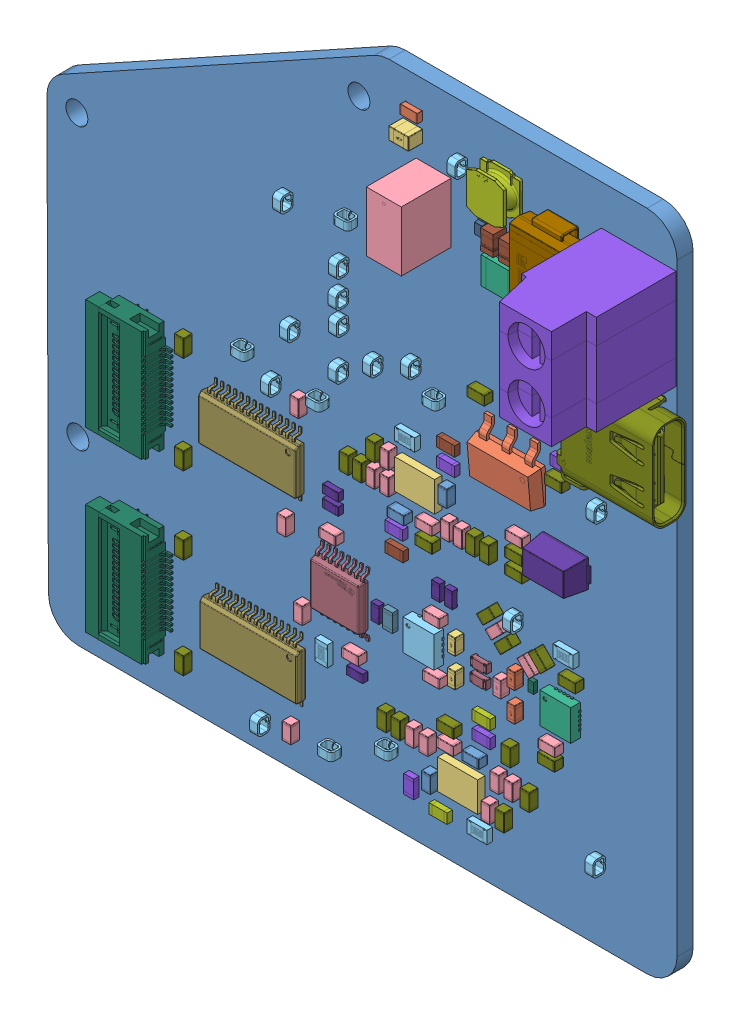
SolidWorks assembly StewartPlatform, configuration Default. Lengths in mm.
Overall size (64.08 66.48 15.5).
190 component instances, 42 part files, 0 mates.
Components (placement in the parent):
- StewartPlatform_BOARD-1: StewartPlatform_BOARD [Default] at origin size (63.17 66.48 1.61)
- RESC1608X55X25NL10T15_CMP-009-00195-1-1: RESC1608X55X25NL10T15_CMP-009-00195-1 [Default] at (81.6864 120.2944 1.5964) x (-1 0 0) z (0 0 1) size (1.7 0.9 0.55)
- FP-CL21-IPC_C_CMP-001-00099-1-1: FP-CL21-IPC_C_CMP-001-00099-1 [Default] at (81.5594 118.5418 1.5964) x (-1 0 0) z (0 0 1) size (2.08 1.33 1.53)
- CAPC1608X90X40NL10T20_CMP-001-00092-1-1: CAPC1608X90X40NL10T20_CMP-001-00092-1 [Default] at (84.2518 77.8764 1.5964) x (-1 0 0) z (0 0 1) size (1.7 0.9 0.9)
- CAPC1608X90X40NL10T20_CMP-001-00092-1-2: CAPC1608X90X40NL10T20_CMP-001-00092-1 [Default] at (84.2518 72.644 1.5964) x (-1 0 0) z (0 0 1) size (1.7 0.9 0.9)
- CAPC1608X90X40NL10T20_CMP-001-00092-1-3: CAPC1608X90X40NL10T20_CMP-001-00092-1 [Default] at (73.8378 79.8322 1.5964) size (1.7 0.9 0.9)
- CAPC1608X90X40NL10T20_CMP-001-00092-1-4: CAPC1608X90X40NL10T20_CMP-001-00092-1 [Default] at (69.2658 78.5622 1.5964) x (0 1 0) z (0 0 1) size (1.7 0.9 0.9)
- CAPC1608X90X40NL10T20_CMP-001-00092-1-5: CAPC1608X90X40NL10T20_CMP-001-00092-1 [Default] at (69.7738 60.7822 1.5964) x (0 1 0) z (0 0 1) size (1.7 0.9 0.9)
- CAPC1608X90X40NL10T20_CMP-001-00092-1-6: CAPC1608X90X40NL10T20_CMP-001-00092-1 [Default] at (76.1238 70.5612 1.5964) x (-1 0 0) z (0 0 1) size (1.7 0.9 0.9)
- CAPC1608X90X40NL10T20_CMP-001-00092-1-7: CAPC1608X90X40NL10T20_CMP-001-00092-1 [Default] at (70.5358 89.4842 1.5964) x (0 -1 0) z (0 0 1) size (1.7 0.9 0.9)
- CAPC1608X90X40NL10T20_CMP-001-00092-1-8: CAPC1608X90X40NL10T20_CMP-001-00092-1 [Default] at (70.9168 71.7042 1.5964) x (0 -1 0) z (0 0 1) size (1.7 0.9 0.9)
- CAPC1608X90X40NL10T20_CMP-001-00092-1-9: CAPC1608X90X40NL10T20_CMP-001-00092-1 [Default] at (65.913 102.1334 0.0102) x (0 -1 0) z (0 0 -1) size (1.7 0.9 0.9)
- CAPC1608X90X40NL10T20_CMP-001-00092-1-10: CAPC1608X90X40NL10T20_CMP-001-00092-1 [Default] at (62.9666 75.8444 0.0102) x (1 0 0) z (0 0 -1) size (1.7 0.9 0.9)
- CAPC1608X90X40NL10T20_CMP-001-00092-1-11: CAPC1608X90X40NL10T20_CMP-001-00092-1 [Default] at (82.0928 66.6242 1.5964) x (0 -1 0) z (0 0 1) size (1.7 0.9 0.9)
- CAPC1608X90X40NL10T20_CMP-001-00092-1-12: CAPC1608X90X40NL10T20_CMP-001-00092-1 [Default] at (83.4898 66.6242 1.5964) x (0 -1 0) z (0 0 1) size (1.7 0.9 0.9)
- CAPC1608X90X40NL10T20_CMP-001-00092-1-13: CAPC1608X90X40NL10T20_CMP-001-00092-1 [Default] at (85.6488 67.5132 1.5964) size (1.7 0.9 0.9)
- CAPC1608X90X40NL10T20_CMP-001-00092-1-14: CAPC1608X90X40NL10T20_CMP-001-00092-1 [Default] at (90.6018 66.8782 1.5964) x (0 1 0) z (0 0 1) size (1.7 0.9 0.9)
- CAPC1608X90X40NL10T20_CMP-001-00092-1-15: CAPC1608X90X40NL10T20_CMP-001-00092-1 [Default] at (91.9988 66.8782 1.5964) x (0 1 0) z (0 0 1) size (1.7 0.9 0.9)
- CAPC1608X90X40NL10T20_CMP-001-00092-1-16: CAPC1608X90X40NL10T20_CMP-001-00092-1 [Default] at (89.7128 63.8302 1.5964) x (0 -1 0) z (0 0 1) size (1.7 0.9 0.9)
- CAPC1608X90X40NL10T20_CMP-001-00092-1-17: CAPC1608X90X40NL10T20_CMP-001-00092-1 [Default] at (86.9188 86.3092 1.5964) x (0 1 0) z (0 0 1) size (1.7 0.9 0.9)
- CAPC1608X90X40NL10T20_CMP-001-00092-1-18: CAPC1608X90X40NL10T20_CMP-001-00092-1 [Default] at (85.6488 86.3092 1.5964) x (0 1 0) z (0 0 1) size (1.7 0.9 0.9)
- CAPC1608X90X40NL10T20_CMP-001-00092-1-19: CAPC1608X90X40NL10T20_CMP-001-00092-1 [Default] at (83.4898 85.5472 1.5964) x (-1 0 0) z (0 0 1) size (1.7 0.9 0.9)
- CAPC1608X90X40NL10T20_CMP-001-00092-1-20: CAPC1608X90X40NL10T20_CMP-001-00092-1 [Default] at (61.5188 60.9092 0.0102) x (1 0 0) z (0 0 -1) size (1.7 0.9 0.9)
- CAPC1608X90X40NL10T20_CMP-001-00092-1-21: CAPC1608X90X40NL10T20_CMP-001-00092-1 [Default] at (78.1558 87.1474 1.5964) x (0 -1 0) z (0 0 1) size (1.7 0.9 0.9)
- CAPC1608X90X40NL10T20_CMP-001-00092-1-22: CAPC1608X90X40NL10T20_CMP-001-00092-1 [Default] at (79.5528 87.1728 1.5964) x (0 -1 0) z (0 0 1) size (1.7 0.9 0.9)
- CAPC1608X90X40NL10T20_CMP-001-00092-1-23: CAPC1608X90X40NL10T20_CMP-001-00092-1 [Default] at (79.5528 89.4842 1.5964) x (0 1 0) z (0 0 1) size (1.7 0.9 0.9)
- CAPC1608X90X40NL10T20_CMP-001-00092-1-24: CAPC1608X90X40NL10T20_CMP-001-00092-1 [Default] at (92.5322 88.9762 1.5964) size (1.7 0.9 0.9)
- CAPC1608X90X40NL10T20_CMP-001-00092-1-25: CAPC1608X90X40NL10T20_CMP-001-00092-1 [Default] at (93.7768 78.5114 1.5964) x (0.707107 -0.707107 0) z (0 0 1) size (1.7 0.9 0.9)
- CAPC1608X90X40NL10T20_CMP-001-00092-1-26: CAPC1608X90X40NL10T20_CMP-001-00092-1 [Default] at (90.5764 79.9846 1.5964) x (0.707107 0.707107 0) z (0 0 1) size (1.7 0.9 0.9)
- CAPC1608X90X40NL10T20_CMP-001-00092-1-27: CAPC1608X90X40NL10T20_CMP-001-00092-1 [Default] at (95.8342 72.4916 1.5964) x (-1 0 0) z (0 0 1) size (1.7 0.9 0.9)
- FP-S2761-46R-MFG_CMP-002-00072-3-1: FP-S2761-46R-MFG_CMP-002-00072-3 [Default] at (74.7522 103.6828 1.5964) x (0 1 0) z (0 0 1) size (1.6 0.8 1.28)
- FP-S2761-46R-MFG_CMP-002-00072-3-2: FP-S2761-46R-MFG_CMP-002-00072-3 [Default] at (75.4888 108.077 1.5964) x (-1 0 0) z (0 0 1) size (1.6 0.8 1.28)
- FP-S2761-46R-MFG_CMP-002-00072-3-3: FP-S2761-46R-MFG_CMP-002-00072-3 [Default] at (74.7268 94.5642 1.5964) x (0 1 0) z (0 0 1) size (1.6 0.8 1.28)
- FP-S2761-46R-MFG_CMP-002-00072-3-4: FP-S2761-46R-MFG_CMP-002-00072-3 [Default] at (74.7522 98.6282 1.5964) x (0 -1 0) z (0 0 1) size (1.6 0.8 1.28)
- FP-S2761-46R-MFG_CMP-002-00072-3-5: FP-S2761-46R-MFG_CMP-002-00072-3 [Default] at (81.9912 98.5774 1.5964) x (0 -1 0) z (0 0 1) size (1.6 0.8 1.28)
- FP-S2761-46R-MFG_CMP-002-00072-3-6: FP-S2761-46R-MFG_CMP-002-00072-3 [Default] at (78.1812 96.8248 1.5964) x (0 1 0) z (0 0 1) size (1.6 0.8 1.28)
- FP-S2761-46R-MFG_CMP-002-00072-3-7: FP-S2761-46R-MFG_CMP-002-00072-3 [Default] at (84.3026 96.8756 1.5964) x (-1 0 0) z (0 0 1) size (1.6 0.8 1.28)
- FP-S2761-46R-MFG_CMP-002-00072-3-8: FP-S2761-46R-MFG_CMP-002-00072-3 [Default] at (74.7268 100.965 1.5964) x (0 -1 0) z (0 0 1) size (1.6 0.8 1.28)
- FP-S2761-46R-MFG_CMP-002-00072-3-9: FP-S2761-46R-MFG_CMP-002-00072-3 [Default] at (69.85 95.7326 1.5964) x (0 1 0) z (0 0 1) size (1.6 0.8 1.28)
- FP-S2761-46R-MFG_CMP-002-00072-3-10: FP-S2761-46R-MFG_CMP-002-00072-3 [Default] at (72.6186 90.932 1.5964) x (-1 0 0) z (0 0 1) size (1.6 0.8 1.28)
- FP-S2761-46R-MFG_CMP-002-00072-3-11: FP-S2761-46R-MFG_CMP-002-00072-3 [Default] at (78.2574 99.187 0.0102) x (0 -1 0) z (0 0 -1) size (1.6 0.8 1.28)
- FP-S2761-46R-MFG_CMP-002-00072-3-12: FP-S2761-46R-MFG_CMP-002-00072-3 [Default] at (69.1642 106.553 1.5964) x (0 -1 0) z (0 0 1) size (1.6 0.8 1.28)
- FP-S2761-46R-MFG_CMP-002-00072-3-13: FP-S2761-46R-MFG_CMP-002-00072-3 [Default] at (79.5274 64.1096 1.5964) x (-1 0 0) z (0 0 1) size (1.6 0.8 1.28)
- FP-S2761-46R-MFG_CMP-002-00072-3-14: FP-S2761-46R-MFG_CMP-002-00072-3 [Default] at (66.8782 60.0456 1.5964) x (0 1 0) z (0 0 1) size (1.6 0.8 1.28)
- FP-S2761-46R-MFG_CMP-002-00072-3-15: FP-S2761-46R-MFG_CMP-002-00072-3 [Default] at (86.6648 118.3132 1.5964) x (0 -1 0) z (0 0 1) size (1.6 0.8 1.28)
- FP-S2761-46R-MFG_CMP-002-00072-3-16: FP-S2761-46R-MFG_CMP-002-00072-3 [Default] at (100.6094 95.3516 1.5964) x (0 -1 0) z (0 0 1) size (1.6 0.8 1.28)
- FP-S2761-46R-MFG_CMP-002-00072-3-17: FP-S2761-46R-MFG_CMP-002-00072-3 [Default] at (73.8378 61.1886 1.5964) x (-1 0 0) z (0 0 1) size (1.6 0.8 1.28)
- FP-S2761-46R-MFG_CMP-002-00072-3-18: FP-S2761-46R-MFG_CMP-002-00072-3 [Default] at (65.1002 91.567 1.5964) x (-1 0 0) z (0 0 1) size (1.6 0.8 1.28)
- FP-S2761-46R-MFG_CMP-002-00072-3-19: FP-S2761-46R-MFG_CMP-002-00072-3 [Default] at (92.2274 81.6102 1.5964) x (0 -1 0) z (0 0 1) size (1.6 0.8 1.28)
- FP-S2761-46R-MFG_CMP-002-00072-3-20: FP-S2761-46R-MFG_CMP-002-00072-3 [Default] at (67.9704 90.043 1.5964) x (0 1 0) z (0 0 1) size (1.6 0.8 1.28)
- FP-S2761-46R-MFG_CMP-002-00072-3-21: FP-S2761-46R-MFG_CMP-002-00072-3 [Default] at (100.4824 64.5668 1.5964) x (0 1 0) z (0 0 1) size (1.6 0.8 1.28)
- RESC3126X60X50NL10T20_CMP-009-00179-1-1: RESC3126X60X50NL10T20_CMP-009-00179-1 [Default] at (90.5764 110.4138 1.5964) x (-1 0 0) z (0 0 1) size (3.2 2.7 0.6)
- FP-LQH44PH_PR-MFG_CMP-06042-017138-1-1: FP-LQH44PH_PR-MFG_CMP-06042-017138-1 [Default] at (90.5764 118.0338 1.5964) x (-1 0 0) z (0 0 1) size (4.01 4 1.95)
- 691137710002_CMP-002-00078-1-1: 691137710002_CMP-002-00078-1 [Default] at (104.2924 114.6048 1.5964) x (0 -1 0) z (0 0 1) size (10 7.5 15.1)
- FP-DO-214AB_SMC_J-Bend-MFG_CMP-004-00033-1-1: FP-DO-214AB_SMC_J-Bend-MFG_CMP-004-00033-1 [Default] at (96.6724 114.6048 1.5964) x (0 -1 0) z (0 0 1) size (7.97 5.92 2.66)
- WL-SMCW_0603_150060xx75000_CMP-007-00036-1-1: WL-SMCW_0603_150060xx75000_CMP-007-00036-1 [Default] at (88.7984 113.8428 1.5964) x (0 1 0) z (0 0 1) size (1.6 0.8 0.7)
- CL21A226MOQNNNE-Footprint-1_CMP-001-00087-3-1: CL21A226MOQNNNE-Footprint-1_CMP-001-00087-3 [Default] at (90.3224 113.8428 1.5964) x (0 1 0) z (0 0 1) size (2 1.25 1.35)
- CL21A226MOQNNNE-Footprint-1_CMP-001-00087-3-2: CL21A226MOQNNNE-Footprint-1_CMP-001-00087-3 [Default] at (92.1004 113.8428 1.5964) x (0 1 0) z (0 0 1) size (2 1.25 1.35)
- TSOP65P640X120-28M_CMP-00000-1-1: TSOP65P640X120-28M_CMP-00000-1 [Default] at (66.2178 66.2432 1.5964) x (0 -1 0) z (0 0 1) size (6.4 9.8 1.2)
- TSOP65P640X120-28M_CMP-00000-1-2: TSOP65P640X120-28M_CMP-00000-1 [Default] at (66.0908 84.0232 1.5964) x (0 -1 0) z (0 0 1) size (6.4 9.8 1.2)
- FP-PW0016A-IPC_B_CMP-002-00081-1-1: FP-PW0016A-IPC_B_CMP-002-00081-1 [Default] at (74.8538 75.2602 1.5964) x (0 -1 0) z (0 0 1) size (6.4 5.01 1.21)
- FP-318-08-IPC_B_CMP-07173-000101-1-1: FP-318-08-IPC_B_CMP-07173-000101-1 [Default] at (53.312 65.1247 0.0102) x (0 1 0) z (0 0 -1) size (2.4 2.92 1.14)
- FP-318-08-IPC_B_CMP-07173-000101-1-2: FP-318-08-IPC_B_CMP-07173-000101-1 [Default] at (56.6166 64.7192 0.0102) x (0 1 0) z (0 0 -1) size (2.4 2.92 1.14)
- FP-318-08-IPC_B_CMP-07173-000101-1-3: FP-318-08-IPC_B_CMP-07173-000101-1 [Default] at (94.9732 99.3403 0.0102) x (0 -1 0) z (0 0 -1) size (2.4 2.92 1.14)
- FP-318-08-IPC_B_CMP-07173-000101-1-4: FP-318-08-IPC_B_CMP-07173-000101-1 [Default] at (75.9688 82.9555 0.0102) x (0 1 0) z (0 0 -1) size (2.4 2.92 1.14)
- FP-318-08-IPC_B_CMP-07173-000101-1-5: FP-318-08-IPC_B_CMP-07173-000101-1 [Default] at (60.3504 85.2424 0.0102) x (0 1 0) z (0 0 -1) size (2.4 2.92 1.14)
- FP-318-08-IPC_B_CMP-07173-000101-1-6: FP-318-08-IPC_B_CMP-07173-000101-1 [Default] at (71.2428 87.188 0.0102) x (-1 0 0) z (0 0 -1) size (2.4 2.92 1.14)
- FP-318-08-IPC_B_CMP-07173-000101-1-7: FP-318-08-IPC_B_CMP-07173-000101-1 [Default] at (71.2724 83.058 0.0102) x (-1 0 0) z (0 0 -1) size (2.4 2.92 1.14)
- FP-318-08-IPC_B_CMP-07173-000101-1-8: FP-318-08-IPC_B_CMP-07173-000101-1 [Default] at (101.1936 71.8016 0.0102) x (0 1 0) z (0 0 -1) size (2.4 2.92 1.14)
- FP-318-08-IPC_B_CMP-07173-000101-1-9: FP-318-08-IPC_B_CMP-07173-000101-1 [Default] at (92.7058 61.6864 0.0102) x (-1 0 0) z (0 0 -1) size (2.4 2.92 1.14)
- FP-318-08-IPC_B_CMP-07173-000101-1-10: FP-318-08-IPC_B_CMP-07173-000101-1 [Default] at (100.5078 62.4586 0.0102) x (0 1 0) z (0 0 -1) size (2.4 2.92 1.14)
- FP-318-08-IPC_B_CMP-07173-000101-1-11: FP-318-08-IPC_B_CMP-07173-000101-1 [Default] at (102.1842 81.2546 0.0102) x (0 -1 0) z (0 0 -1) size (2.4 2.92 1.14)
- FP-318-08-IPC_B_CMP-07173-000101-1-12: FP-318-08-IPC_B_CMP-07173-000101-1 [Default] at (78.2828 63.0428 0.0102) x (0 -1 0) z (0 0 -1) size (2.4 2.92 1.14)
- 687114149022_CMP-002-00080-1-1: 687114149022_CMP-002-00080-1 [Default] at (53.8988 66.3702 1.5964) x (0 -1 0) z (0 0 1) size (11.1 6.5 2.25)
- 687114149022_CMP-002-00080-1-2: 687114149022_CMP-002-00080-1 [Default] at (53.8988 84.1502 1.5964) x (0 -1 0) z (0 0 1) size (11.1 6.5 2.25)
- CAPC1608X90X35NL15T15_CMP-001-00004-8-1: CAPC1608X90X35NL15T15_CMP-001-00004-8 [Default] at (58.9788 61.4172 1.5964) x (0 1 0) z (0 0 1) size (1.75 0.95 0.9)
- CAPC1608X90X35NL15T15_CMP-001-00004-8-2: CAPC1608X90X35NL15T15_CMP-001-00004-8 [Default] at (58.9788 88.9762 1.5964) x (0 -1 0) z (0 0 1) size (1.75 0.95 0.9)
- CAPC1608X90X35NL15T15_CMP-001-00004-8-3: CAPC1608X90X35NL15T15_CMP-001-00004-8 [Default] at (58.9788 79.1972 1.5964) x (0 1 0) z (0 0 1) size (1.75 0.95 0.9)
- CAPC1608X90X35NL15T15_CMP-001-00004-8-4: CAPC1608X90X35NL15T15_CMP-001-00004-8 [Default] at (58.9788 71.4502 1.5964) x (0 -1 0) z (0 0 1) size (1.75 0.95 0.9)
- CAPC1608X90X35NL15T15_CMP-001-00004-8-5: CAPC1608X90X35NL15T15_CMP-001-00004-8 [Default] at (73.914 107.3658 0.0102) x (-1 0 0) z (0 0 -1) size (1.75 0.95 0.9)
- CAPC1608X90X35NL15T15_CMP-001-00004-8-6: CAPC1608X90X35NL15T15_CMP-001-00004-8 [Default] at (68.2244 71.4502 0.0102) x (1 0 0) z (0 0 -1) size (1.75 0.95 0.9)
- CAPC1608X90X35NL15T15_CMP-001-00004-8-7: CAPC1608X90X35NL15T15_CMP-001-00004-8 [Default] at (62.992 73.3298 0.0102) x (1 0 0) z (0 0 -1) size (1.75 0.95 0.9)
- CAPC1608X90X35NL15T15_CMP-001-00004-8-8: CAPC1608X90X35NL15T15_CMP-001-00004-8 [Default] at (62.992 74.6252 0.0102) x (1 0 0) z (0 0 -1) size (1.75 0.95 0.9)
- CAPC1608X90X35NL15T15_CMP-001-00004-8-9: CAPC1608X90X35NL15T15_CMP-001-00004-8 [Default] at (60.96 75.2856 0.0102) x (0 1 0) z (0 0 -1) size (1.75 0.95 0.9)
- CAPC1608X90X35NL15T15_CMP-001-00004-8-10: CAPC1608X90X35NL15T15_CMP-001-00004-8 [Default] at (79.2988 66.6242 1.5964) x (0 -1 0) z (0 0 1) size (1.75 0.95 0.9)
- CAPC1608X90X35NL15T15_CMP-001-00004-8-11: CAPC1608X90X35NL15T15_CMP-001-00004-8 [Default] at (80.6958 66.6242 1.5964) x (0 -1 0) z (0 0 1) size (1.75 0.95 0.9)
- CAPC1608X90X35NL15T15_CMP-001-00004-8-12: CAPC1608X90X35NL15T15_CMP-001-00004-8 [Default] at (85.6488 69.0372 1.5964) size (1.75 0.95 0.9)
- CAPC1608X90X35NL15T15_CMP-001-00004-8-13: CAPC1608X90X35NL15T15_CMP-001-00004-8 [Default] at (91.7448 69.7992 1.5964) x (0 -1 0) z (0 0 1) size (1.75 0.95 0.9)
- CAPC1608X90X35NL15T15_CMP-001-00004-8-14: CAPC1608X90X35NL15T15_CMP-001-00004-8 [Default] at (93.6498 66.8782 1.5964) x (0 1 0) z (0 0 1) size (1.75 0.95 0.9)
- CAPC1608X90X35NL15T15_CMP-001-00004-8-15: CAPC1608X90X35NL15T15_CMP-001-00004-8 [Default] at (91.1098 63.8302 1.5964) x (0 -1 0) z (0 0 1) size (1.75 0.95 0.9)
- CAPC1608X90X35NL15T15_CMP-001-00004-8-16: CAPC1608X90X35NL15T15_CMP-001-00004-8 [Default] at (69.596 58.039 0.0102) x (-1 0 0) z (0 0 -1) size (1.75 0.95 0.9)
- CAPC1608X90X35NL15T15_CMP-001-00004-8-17: CAPC1608X90X35NL15T15_CMP-001-00004-8 [Default] at (89.5858 86.3092 1.5964) x (0 1 0) z (0 0 1) size (1.75 0.95 0.9)
- CAPC1608X90X35NL15T15_CMP-001-00004-8-18: CAPC1608X90X35NL15T15_CMP-001-00004-8 [Default] at (88.1888 86.3092 1.5964) x (0 1 0) z (0 0 1) size (1.75 0.95 0.9)
- CAPC1608X90X35NL15T15_CMP-001-00004-8-19: CAPC1608X90X35NL15T15_CMP-001-00004-8 [Default] at (83.4898 84.0232 1.5964) x (-1 0 0) z (0 0 1) size (1.75 0.95 0.9)
- CAPC1608X90X35NL15T15_CMP-001-00004-8-20: CAPC1608X90X35NL15T15_CMP-001-00004-8 [Default] at (67.5386 66.3194 0.0102) x (0 -1 0) z (0 0 -1) size (1.75 0.95 0.9)
- CAPC1608X90X35NL15T15_CMP-001-00004-8-21: CAPC1608X90X35NL15T15_CMP-001-00004-8 [Default] at (61.5442 59.6646 0.0102) x (1 0 0) z (0 0 -1) size (1.75 0.95 0.9)
- CAPC1608X90X35NL15T15_CMP-001-00004-8-22: CAPC1608X90X35NL15T15_CMP-001-00004-8 [Default] at (59.0042 62.6364 0.0102) x (0 1 0) z (0 0 -1) size (1.75 0.95 0.9)
- CAPC1608X90X35NL15T15_CMP-001-00004-8-23: CAPC1608X90X35NL15T15_CMP-001-00004-8 [Default] at (75.5142 87.0712 1.5964) x (0 -1 0) z (0 0 1) size (1.75 0.95 0.9)
- CAPC1608X90X35NL15T15_CMP-001-00004-8-24: CAPC1608X90X35NL15T15_CMP-001-00004-8 [Default] at (76.835 87.0712 1.5964) x (0 -1 0) z (0 0 1) size (1.75 0.95 0.9)
- CAPC1608X90X35NL15T15_CMP-001-00004-8-25: CAPC1608X90X35NL15T15_CMP-001-00004-8 [Default] at (78.1558 89.4842 1.5964) x (0 1 0) z (0 0 1) size (1.75 0.95 0.9)
- CAPC1608X90X35NL15T15_CMP-001-00004-8-26: CAPC1608X90X35NL15T15_CMP-001-00004-8 [Default] at (96.4692 95.7834 1.5964) x (-1 0 0) z (0 0 1) size (1.75 0.95 0.9)
- CAPC1608X90X35NL15T15_CMP-001-00004-8-27: CAPC1608X90X35NL15T15_CMP-001-00004-8 [Default] at (92.5068 87.4522 1.5964) size (1.75 0.95 0.9)
- CAPC1608X90X35NL15T15_CMP-001-00004-8-28: CAPC1608X90X35NL15T15_CMP-001-00004-8 [Default] at (92.5068 85.9536 1.5964) size (1.75 0.95 0.9)
- CAPC1608X90X35NL15T15_CMP-001-00004-8-29: CAPC1608X90X35NL15T15_CMP-001-00004-8 [Default] at (88.7222 99.4918 1.5964) size (1.75 0.95 0.9)
- CAPC1608X90X35NL15T15_CMP-001-00004-8-30: CAPC1608X90X35NL15T15_CMP-001-00004-8 [Default] at (97.8408 79.0702 1.5964) x (-1 0 0) z (0 0 1) size (1.75 0.95 0.9)
- CAPC1608X90X35NL15T15_CMP-001-00004-8-31: CAPC1608X90X35NL15T15_CMP-001-00004-8 [Default] at (94.9198 79.5528 1.5964) x (-0.707107 0.707107 0) z (0 0 1) size (1.75 0.95 0.9)
- CAPC1608X90X35NL15T15_CMP-001-00004-8-32: CAPC1608X90X35NL15T15_CMP-001-00004-8 [Default] at (91.4908 79.2226 1.5964) x (0.707107 0.707107 0) z (0 0 1) size (1.75 0.95 0.9)
- CAPC1608X90X35NL15T15_CMP-001-00004-8-33: CAPC1608X90X35NL15T15_CMP-001-00004-8 [Default] at (89.7382 80.899 1.5964) x (0.707107 0.707107 0) z (0 0 1) size (1.75 0.95 0.9)
- CAPC1608X90X35NL15T15_CMP-001-00004-8-34: CAPC1608X90X35NL15T15_CMP-001-00004-8 [Default] at (95.7834 71.247 1.5964) x (-1 0 0) z (0 0 1) size (1.75 0.95 0.9)
- RC0603JR-0720KL-Footprint-1_CMP-009-00199-1-1: RC0603JR-0720KL-Footprint-1_CMP-009-00199-1 [Default] at (85.6488 80.2132 1.5964) x (0 1 0) z (0 0 1) size (1.6 0.8 0.55)
- RC0603JR-0720KL-Footprint-1_CMP-009-00199-1-2: RC0603JR-0720KL-Footprint-1_CMP-009-00199-1 [Default] at (84.3788 80.2132 1.5964) x (0 1 0) z (0 0 1) size (1.6 0.8 0.55)
- RC0603JR-0720KL-Footprint-1_CMP-009-00199-1-3: RC0603JR-0720KL-Footprint-1_CMP-009-00199-1 [Default] at (76.2508 68.9102 1.5964) size (1.6 0.8 0.55)
- RC0603JR-0720KL-Footprint-1_CMP-009-00199-1-4: RC0603JR-0720KL-Footprint-1_CMP-009-00199-1 [Default] at (73.8124 82.2198 1.5964) size (1.6 0.8 0.55)
- RC0603JR-0720KL-Footprint-1_CMP-009-00199-1-5: RC0603JR-0720KL-Footprint-1_CMP-009-00199-1 [Default] at (78.2828 75.2455 1.5964) x (0 -1 0) z (0 0 1) size (1.6 0.8 0.55)
- RC0603JR-0720KL-Footprint-1_CMP-009-00199-1-6: RC0603JR-0720KL-Footprint-1_CMP-009-00199-1 [Default] at (73.8378 83.4644 1.5964) size (1.6 0.8 0.55)
- FP-BLM21-0_2-t0_85-e0_5-MFG_CMP-00019-1-1: FP-BLM21-0_2-t0_85-e0_5-MFG_CMP-00019-1 [Default] at (96.0628 86.1822 0.0102) x (1 0 0) z (0 0 -1) size (2.01 1.26 1.05)
- 44ML_M_CMP-0095-00285-2-1: 44ML_M_CMP-0095-00285-2 [Default] at (73.8632 99.4156 0.0102) x (0 -1 0) z (0 0 -1) size (10 10 1.2)
- LM317DCYR-Footprint-1_CMP-019-00056-1-1: LM317DCYR-Footprint-1_CMP-019-00056-1 [Default] at (63.6778 80.8902 0.0102) x (0 1 0) z (0 0 -1) size (6.97 6.5 2.23)
- LM317DCYR-Footprint-1_CMP-019-00056-1-2: LM317DCYR-Footprint-1_CMP-019-00056-1 [Default] at (62.9412 65.8026 0.0102) x (0 1 0) z (0 0 -1) size (6.97 6.5 2.23)
- LM317DCYR-Footprint-1_CMP-019-00056-1-3: LM317DCYR-Footprint-1_CMP-019-00056-1 [Default] at (91.6686 94.4416 1.5964) x (0 -1 0) z (0 0 1) size (6.97 6.5 2.23)
- LT-DE14MA-14_V_CMP-0476-00341-1-1: LT-DE14MA-14_V_CMP-0476-00341-1 [Default] at (86.7918 64.6382 1.5964) x (0 -1 0) z (0 0 1) size (3 4 0.75)
- LT-DE14MA-14_V_CMP-0476-00341-1-2: LT-DE14MA-14_V_CMP-0476-00341-1 [Default] at (82.4738 88.5492 1.5964) x (0 1 0) z (0 0 1) size (3 4 0.75)
- FSM2JMTR-Footprint-1_CMP-00028-00007-1-1: FSM2JMTR-Footprint-1_CMP-00028-00007-1 [Default] at (83.6422 113.3094 1.5964) x (0 -1 0) z (0 0 1) size (6.81 3.51 5.01)
- RES_0805_2012_RM10F1002CT-1-1: RES_0805_2012_RM10F1002CT-1 [Default] at (60.3504 88.4174 0.0102) x (1 0 0) z (0 0 -1) size (2 1.25 0.6)
- RES_0805_2012_RM10F1002CT-1-2: RES_0805_2012_RM10F1002CT-1 [Default] at (68.0466 87.122 0.0102) x (0 1 0) z (0 0 -1) size (2 1.25 0.6)
- RES_0805_2012_RM10F1002CT-1-3: RES_0805_2012_RM10F1002CT-1 [Default] at (68.0974 83.058 0.0102) x (0 1 0) z (0 0 -1) size (2 1.25 0.6)
- RES_0805_2012_RM10F1002CT-1-4: RES_0805_2012_RM10F1002CT-1 [Default] at (80.6196 105.6132 0.0102) x (1 0 0) z (0 0 -1) size (2 1.25 0.6)
- RES_0805_2012_RM10F1002CT-1-5: RES_0805_2012_RM10F1002CT-1 [Default] at (88.5698 61.4426 1.5964) x (-1 0 0) z (0 0 1) size (2 1.25 0.6)
- RES_0805_2012_RM10F1002CT-1-6: RES_0805_2012_RM10F1002CT-1 [Default] at (81.3308 91.8972 1.5964) size (2 1.25 0.6)
- RES_0805_2012_RM10F1002CT-1-7: RES_0805_2012_RM10F1002CT-1 [Default] at (53.312 68.2997 0.0102) x (1 0 0) z (0 0 -1) size (2 1.25 0.6)
- RES_0805_2012_RM10F1002CT-1-8: RES_0805_2012_RM10F1002CT-1 [Default] at (56.6166 67.8942 0.0102) x (1 0 0) z (0 0 -1) size (2 1.25 0.6)
- RES_0805_2012_RM10F1002CT-1-9: RES_0805_2012_RM10F1002CT-1 [Default] at (94.9732 96.1653 0.0102) x (-1 0 0) z (0 0 -1) size (2 1.25 0.6)
- RES_0805_2012_RM10F1002CT-1-10: RES_0805_2012_RM10F1002CT-1 [Default] at (75.9688 86.1305 0.0102) x (1 0 0) z (0 0 -1) size (2 1.25 0.6)
- RES_0805_2012_RM10F1002CT-1-11: RES_0805_2012_RM10F1002CT-1 [Default] at (49.4284 64.6176 0.0102) x (-1 0 0) z (0 0 -1) size (2 1.25 0.6)
- RES_0805_2012_RM10F1002CT-1-12: RES_0805_2012_RM10F1002CT-1 [Default] at (49.4284 62.8396 0.0102) x (-1 0 0) z (0 0 -1) size (2 1.25 0.6)
- RES_0805_2012_RM10F1002CT-1-13: RES_0805_2012_RM10F1002CT-1 [Default] at (49.4284 61.1378 0.0102) x (-1 0 0) z (0 0 -1) size (2 1.25 0.6)
- RES_0805_2012_RM10F1002CT-1-14: RES_0805_2012_RM10F1002CT-1 [Default] at (72.9488 69.1642 1.5964) x (0 -1 0) z (0 0 1) size (2 1.25 0.6)
- RES_0805_2012_RM10F1002CT-1-15: RES_0805_2012_RM10F1002CT-1 [Default] at (49.4284 59.3852 0.0102) x (-1 0 0) z (0 0 -1) size (2 1.25 0.6)
- RES_0805_2012_RM10F1002CT-1-16: RES_0805_2012_RM10F1002CT-1 [Default] at (101.1936 74.9554 0.0102) x (-1 0 0) z (0 0 -1) size (2 1.25 0.6)
- RES_0805_2012_RM10F1002CT-1-17: RES_0805_2012_RM10F1002CT-1 [Default] at (100.3046 68.6054 0.0102) x (1 0 0) z (0 0 -1) size (2 1.25 0.6)
- RES_0805_2012_RM10F1002CT-1-18: RES_0805_2012_RM10F1002CT-1 [Default] at (89.5096 61.6204 0.0102) x (0 -1 0) z (0 0 -1) size (2 1.25 0.6)
- RES_0805_2012_RM10F1002CT-1-19: RES_0805_2012_RM10F1002CT-1 [Default] at (95.8596 60.8584 0.0102) x (0 1 0) z (0 0 -1) size (2 1.25 0.6)
- RES_0805_2012_RM10F1002CT-1-20: RES_0805_2012_RM10F1002CT-1 [Default] at (100.5078 65.6336 0.0102) x (-1 0 0) z (0 0 -1) size (2 1.25 0.6)
- RES_0805_2012_RM10F1002CT-1-21: RES_0805_2012_RM10F1002CT-1 [Default] at (99.5934 59.817 0.0102) x (1 0 0) z (0 0 -1) size (2 1.25 0.6)
- RES_0805_2012_RM10F1002CT-1-22: RES_0805_2012_RM10F1002CT-1 [Default] at (54.483 86.6902 0.0102) x (-1 0 0) z (0 0 -1) size (2 1.25 0.6)
- RES_0805_2012_RM10F1002CT-1-23: RES_0805_2012_RM10F1002CT-1 [Default] at (54.483 81.6102 0.0102) x (-1 0 0) z (0 0 -1) size (2 1.25 0.6)
- RES_0805_2012_RM10F1002CT-1-24: RES_0805_2012_RM10F1002CT-1 [Default] at (54.483 83.2612 0.0102) x (-1 0 0) z (0 0 -1) size (2 1.25 0.6)
- RES_0805_2012_RM10F1002CT-1-25: RES_0805_2012_RM10F1002CT-1 [Default] at (102.0572 78.0796 0.0102) x (1 0 0) z (0 0 -1) size (2 1.25 0.6)
- RES_0805_2012_RM10F1002CT-1-26: RES_0805_2012_RM10F1002CT-1 [Default] at (101.1682 84.3534 0.0102) x (1 0 0) z (0 0 -1) size (2 1.25 0.6)
- RES_0805_2012_RM10F1002CT-1-27: RES_0805_2012_RM10F1002CT-1 [Default] at (78.1558 59.8678 0.0102) x (1 0 0) z (0 0 -1) size (2 1.25 0.6)
- RES_0805_2012_RM10F1002CT-1-28: RES_0805_2012_RM10F1002CT-1 [Default] at (79.1718 66.2178 0.0102) x (-1 0 0) z (0 0 -1) size (2 1.25 0.6)
- RES_0805_2012_RM10F1002CT-1-29: RES_0805_2012_RM10F1002CT-1 [Default] at (54.4576 84.963 0.0102) x (-1 0 0) z (0 0 -1) size (2 1.25 0.6)
- RES_0805_2012_RM10F1002CT-1-30: RES_0805_2012_RM10F1002CT-1 [Default] at (97.2058 80.9752 1.5964) size (2 1.25 0.6)
- RES_0805_2012_RC0805JR-075K1L-1-1: RES_0805_2012_RC0805JR-075K1L-1 [Default] at (101.219 109.347 0.0102) x (-1 0 0) z (0 0 -1) size (2 1.25 0.6)
- RES_0805_2012_RC0805JR-075K1L-1-2: RES_0805_2012_RC0805JR-075K1L-1 [Default] at (95.6056 104.521 0.0102) x (-0.707107 0.707107 0) z (0 0 -1) size (2 1.25 0.6)
- RESC1608X06M_CMP-00011-1-1: RESC1608X06M_CMP-00011-1 [Default] at (84.6328 61.0362 1.5964) x (-1 0 0) z (0 0 1) size (1.8 1 0.55)
- RESC1608X06M_CMP-00011-1-2: RESC1608X06M_CMP-00011-1 [Default] at (88.9508 71.3232 1.5964) x (-1 0 0) z (0 0 1) size (1.8 1 0.55)
- RESC1608X06M_CMP-00008-1-1: RESC1608X06M_CMP-00008-1 [Default] at (68.1736 72.8218 0.0102) x (1 0 0) z (0 0 -1) size (1.8 1 0.55)
- RESC1608X06M_CMP-00008-1-2: RESC1608X06M_CMP-00008-1 [Default] at (81.6864 61.8998 1.5964) x (0 1 0) z (0 0 1) size (1.8 1 0.55)
- RESC1608X06M_CMP-00008-1-3: RESC1608X06M_CMP-00008-1 [Default] at (88.9508 69.6722 1.5964) size (1.8 1 0.55)
- RESC1608X06M_CMP-00008-1-4: RESC1608X06M_CMP-00008-1 [Default] at (66.5348 58.039 0.0102) x (1 0 0) z (0 0 -1) size (1.8 1 0.55)
- RESC1608X06M_CMP-00008-1-5: RESC1608X06M_CMP-00008-1 [Default] at (96.7486 97.409 1.5964) x (-1 0 0) z (0 0 1) size (1.8 1 0.55)
- RESC1608X06M_CMP-00008-1-6: RESC1608X06M_CMP-00008-1 [Default] at (85.3948 91.5162 1.5964) size (1.8 1 0.55)
- RESC1608X06M_CMP-00008-1-7: RESC1608X06M_CMP-00008-1 [Default] at (80.1878 83.3882 1.5964) x (-1 0 0) z (0 0 1) size (1.8 1 0.55)
- RESC1608X06M_CMP-00013-1-1: RESC1608X06M_CMP-00013-1 [Default] at (64.6286 85.979 0.0102) x (-1 0 0) z (0 0 -1) size (1.8 1 0.55)
- RESC1608X06M_CMP-00012-1-1: RESC1608X06M_CMP-00012-1 [Default] at (67.5132 63.6778 0.0102) x (0 1 0) z (0 0 -1) size (1.8 1 0.55)
- RESC1608X06M_CMP-00009-1-1: RESC1608X06M_CMP-00009-1 [Default] at (85.3948 93.2942 1.5964) size (1.8 1 0.55)
- RESC1608X06M_CMP-00009-1-2: RESC1608X06M_CMP-00009-1 [Default] at (80.2132 81.534 1.5964) x (-1 0 0) z (0 0 1) size (1.8 1 0.55)
- RESC1608X06M_CMP-00006-1-1: RESC1608X06M_CMP-00006-1 [Default] at (93.0656 99.9026 1.5964) x (-1 0 0) z (0 0 1) size (1.8 1 0.55)
- FP-RT0603-MFG_CMP-03412-013551-1-1: FP-RT0603-MFG_CMP-03412-013551-1 [Default] at (88.5698 74.4982 1.5964) size (1.6 0.8 0.58)
- FP-RT0603-MFG_CMP-03412-013551-1-2: FP-RT0603-MFG_CMP-03412-013551-1 [Default] at (88.6088 75.8952 1.5964) size (1.6 0.8 0.58)
- RESC1608X06M_CMP-00007-1-1: RESC1608X06M_CMP-00007-1 [Default] at (79.5528 75.2602 1.5964) x (0 -1 0) z (0 0 1) size (1.8 1 0.55)
- RESC1005X40X25NL05T10_CMP-1011-00013-2-1: RESC1005X40X25NL05T10_CMP-1011-00013-2 [Default] at (93.7768 76.5302 1.5964) x (0 -1 0) z (0 0 1) size (1.05 0.55 0.4)
- FP-217183-0001-MFG_CMP-04767-000015-1-1: FP-217183-0001-MFG_CMP-04767-000015-1 [Default] at (104.021 103.333 1.5964) x (0 1 0) z (0 0 1) size (9.85 9.87 4.77)
- SODFL500X231-2L_CMP-004-00037-1-1: SODFL500X231-2L_CMP-004-00037-1 [Default] at (67.1068 75.1586 0.0102) x (1 0 0) z (0 0 -1) size (5 2.79 2.31)
- SODFL500X231-2L_CMP-004-00037-1-2: SODFL500X231-2L_CMP-004-00037-1 [Default] at (65.5574 60.2234 0.0102) x (1 0 0) z (0 0 -1) size (5 2.79 2.31)
- SODFL500X231-2L_CMP-004-00037-1-3: SODFL500X231-2L_CMP-004-00037-1 [Default] at (96.901 88.9 1.5964) size (5 2.79 2.31)
- FP-CBR06C-MFG_CMP-03020-002160-1-1: FP-CBR06C-MFG_CMP-03020-002160-1 [Default] at (86.3092 95.9962 0.0102) x (0 -1 0) z (0 0 -1) size (1.73 0.92 0.99)
- FP-CBR06C-MFG_CMP-03020-002160-1-2: FP-CBR06C-MFG_CMP-03020-002160-1 [Default] at (86.3854 99.9236 0.0102) x (0 1 0) z (0 0 -1) size (1.73 0.92 0.99)
- CAPC1608X90X40NL10T20_CMP-001-00096-1-1: CAPC1608X90X40NL10T20_CMP-001-00096-1 [Default] at (83.7438 63.4492 1.5964) x (0 1 0) z (0 0 1) size (1.7 0.9 0.9)
- CAPC1608X90X40NL10T20_CMP-001-00096-1-2: CAPC1608X90X40NL10T20_CMP-001-00096-1 [Default] at (88.1888 67.6402 1.5964) size (1.7 0.9 0.9)
- CAPC1608X90X40NL10T20_CMP-001-00096-1-3: CAPC1608X90X40NL10T20_CMP-001-00096-1 [Default] at (85.3948 89.1032 1.5964) x (0 -1 0) z (0 0 1) size (1.7 0.9 0.9)
- CAPC1608X90X40NL10T20_CMP-001-00096-1-4: CAPC1608X90X40NL10T20_CMP-001-00096-1 [Default] at (80.6958 85.0392 1.5964) x (-1 0 0) z (0 0 1) size (1.7 0.9 0.9)
- FP-CL10-IPC_B_CMP-001-00093-1-1: FP-CL10-IPC_B_CMP-001-00093-1 [Default] at (92.2528 73.7362 1.5964) x (0 1 0) z (0 0 1) size (1.68 0.88 0.97)
- FP-CL10-IPC_B_CMP-001-00093-1-2: FP-CL10-IPC_B_CMP-001-00093-1 [Default] at (92.2528 76.6572 1.5964) x (0 1 0) z (0 0 1) size (1.68 0.88 0.97)
- FP-CL10-IPC_B_CMP-001-00091-1-1: FP-CL10-IPC_B_CMP-001-00091-1 [Default] at (86.2838 73.7362 1.5964) x (0 1 0) z (0 0 1) size (1.68 0.88 0.97)
- FP-CL10-IPC_B_CMP-001-00091-1-2: FP-CL10-IPC_B_CMP-001-00091-1 [Default] at (86.2838 76.6572 1.5964) x (0 1 0) z (0 0 1) size (1.68 0.88 0.97)
- FP-CL10-IPC_B_CMP-001-00094-2-1: FP-CL10-IPC_B_CMP-001-00094-2 [Default] at (90.8558 75.2252 1.5964) x (0 1 0) z (0 0 1) size (1.68 0.88 0.97)
- QFN50P300X300X100_HS-17M_CMP-00005-1-1: QFN50P300X300X100_HS-17M_CMP-00005-1 [Default] at (83.1088 75.2602 1.5964) size (3.18 3.18 1)
- QFN40P300X300X100_HS-21M_CMP-00010-1-1: QFN40P300X300X100_HS-21M_CMP-00010-1 [Default] at (96.8248 75.7682 1.5964) size (3.18 3.18 1)
